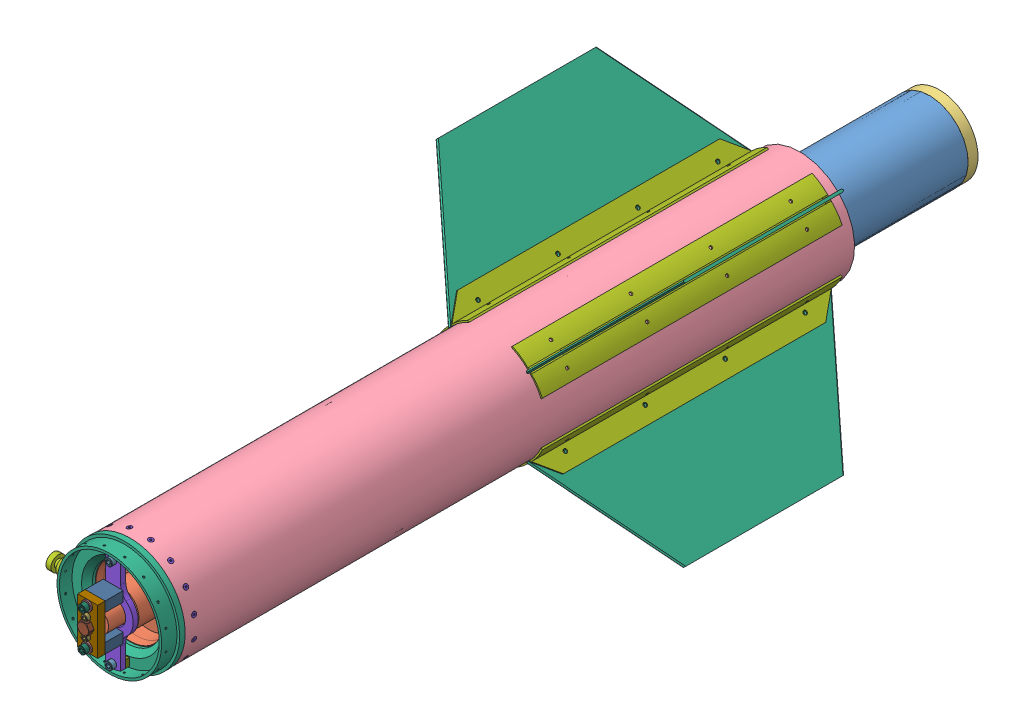
SolidWorks assembly RouseTech_Motor_Retainmenta_Asm, configuration Default. Lengths in mm.
Overall size (316.55 316.55 1102.99).
68 component instances, 28 part files, 35 mates.
Components (placement in the parent):
- RouseTech_15360_Motor_Casing-1: RouseTech_15360_Motor_Casing [Default] at (0 0 12.7) x (0.954187 -0.29921 0) z (0 0 1) size (98.42 98.42 1005.33)
- RouseTech_98mm_Forward_Closure-1: RouseTech_98mm_Forward_Closure [Default] at (0 0 985.1263) x (-1 0.000002 0) z (0 0 1) size (98.27 98.27 85.09)
- RouseTech_98mm_Aft_Closure-1: RouseTech_98mm_Aft_Closure [Default] x (-1 0.000002 0) z (0 0 1) size (98 98 35.31)
- Motor_Fairing-1: Motor_Fairing [Default] at (0 0 1028.4841) x (0.980785 -0.19509 0) z (0 0 -1) size (139.7 139.7 850.9)
- Aft_Motor_Centering_Ring-1: Aft_Motor_Centering_Ring [Default] at (0 0 177.5968) x (0 -1 0) z (0 0 1) size (136.27 136.27 15.88)
- Motor_Bulkhead-1: Motor_Bulkhead [Default] at (0 0 1008.9261) x (-0.19509 -0.980785 0) z (0 0 1) size (139.7 139.7 46.1)
- Rail_Button-1: Rail_Button [Default] at (-69.1975 0 1032.0401) x (0 1 0) z (-1 0 0) size (19.05 19.05 25.33)
- Rail_Button-2: Rail_Button [Default] at (-69.1975 0 188.7093) x (0 1 0) z (-1 0 0) size (19.05 19.05 25.33)
- RouseTech_Retainer_Bracket2-1: RouseTech_Retainer_Bracket2 [Default] at (13.9486 -3.8393 1028.2531) x (0 1 0) z (0 0 1) size (127 50.8 67.37)
  - Retainment_Strap-1: Retainment_Strap [Default] at (-59.6607 23.4736 15.5345) size (127 50.8 6.35)
  - RouseTech_Retaining_CrossBar2-1: RouseTech_Retaining_CrossBar2 [Default] at (33.0493 13.9486 49.507) x (0 -1 0) z (-1 0 0) size (25.4 9.53 58.42)
  - Motor_Retainer_Standoff-1: Motor_Retainer_Standoff [Default] at (-19.0207 13.9486 21.8845) x (0 -1 0) z (0 0 1) size (25.4 12.7 22.86)
  - Motor_Retainer_Standoff-2: Motor_Retainer_Standoff [Default] at (26.6993 13.9486 21.8845) x (0 1 0) z (0 0 1) size (25.4 12.7 22.86)
  - 0.375in-16_1.25in_Bolt_MC-92620A626-1: 0.375in-16_1.25in_Bolt_MC-92620A626 [92620A626] at (3.8393 13.9486 38.3945) size (14.29 16.24 37.79)
  - 10-24_0.375in_Allen_Head_Cap_Screw_MC-91251A240-1: 10-24_0.375in_Allen_Head_Cap_Screw_MC-91251A240 [91251A240] at (-7.2097 13.9486 44.7445) x (-0.923728 -0.383049 0) z (0 0 -1) size (7.92 7.92 15.51)
  - 10-24_0.375in_Allen_Head_Cap_Screw_MC-91251A240-2: 10-24_0.375in_Allen_Head_Cap_Screw_MC-91251A240 [91251A240] at (14.8883 13.9486 44.7445) x (-0.923728 -0.383049 0) z (0 0 -1) size (7.92 7.92 15.51)
  - 0.25in_Lock_Washer-1: 0.25in_Lock_Washer [Default] at (26.6993 13.9486 56.1237) x (-0.923728 -0.383049 0) z (0 0 -1) size (12.32 12.32 1.85)
  - 0.25in_Lock_Washer-2: 0.25in_Lock_Washer [Default] at (-19.0207 13.9486 56.1237) x (-0.923728 -0.383049 0) z (0 0 -1) size (12.32 12.32 1.85)
  - 0.25-20_1.0in_Allen Head_Cap_Screw_MC-91251A542-1: 0.25-20_1.0in_Allen Head_Cap_Screw_MC-91251A542 [91251A542] at (60.9893 13.9486 -3.5155) x (-0.923728 -0.383049 0) z (0 0 -1) size (9.53 9.53 33.14)
  - 0.25-20_1.0in_Allen Head_Cap_Screw_MC-91251A542-2: 0.25-20_1.0in_Allen Head_Cap_Screw_MC-91251A542 [91251A542] at (-53.3107 13.9486 -3.5155) x (-0.923728 -0.383049 0) z (0 0 -1) size (9.53 9.53 33.14)
  - 0.25-20_1.75in_Allen Head_Cap_Screw_MC-91251A548-1: 0.25-20_1.75in_Allen Head_Cap_Screw_MC-91251A548 [91251A548] at (26.6993 13.9486 11.6737) x (-0.923728 -0.383049 0) z (0 0 -1) size (9.53 9.53 52.19)
  - 0.25-20_1.75in_Allen Head_Cap_Screw_MC-91251A548-2: 0.25-20_1.75in_Allen Head_Cap_Screw_MC-91251A548 [91251A548] at (-19.0207 13.9486 11.6737) x (-0.950943 -0.309366 0) z (0 0 -1) size (9.53 9.53 52.19)
  - RouseTech_Retainer_Spacer-1: RouseTech_Retainer_Spacer [Default] at (60.2908 13.9486 10.772) x (0 -1 0) z (0 0 1) size (19.05 9.53 4.76)
  - RouseTech_Retainer_Spacer-2: RouseTech_Retainer_Spacer [Default] at (-52.6122 13.9486 10.772) x (0 1 0) z (0 0 1) size (19.05 9.53 4.76)
- N2000W_Reload_Assembeled-1: N2000W_Reload_Assembeled [Default] at (0 0 56.2356) x (-0.683365 0.730076 0) z (0.730076 0.683365 0) size (129.43 1050.01 129.43)
  - N2000W_Grain-1: N2000W_Grain [Default] at origin size (85.22 152.4 85.22)
  - N2000W_Grain-2: N2000W_Grain [Default] at (0 457.2 0) x (0.999641 0 -0.02679) z (0.02679 0 0.999641) size (85.22 152.4 85.22)
  - N2000W_Grain-3: N2000W_Grain [Default] at (0 152.4 0) size (85.22 152.4 85.22)
  - N2000W_Grain-4: N2000W_Grain [Default] at (0 609.6 0) x (0.569996 0 0.821647) z (-0.821647 0 0.569996) size (85.22 152.4 85.22)
  - N2000W_Grain-6: N2000W_Grain [Default] at (0 304.8 0) size (85.22 152.4 85.22)
  - N2000W_Reload_Liner-1: N2000W_Reload_Liner [Default] at (0 -9.144 0) x (0.685714 0 0.727871) z (-0.727871 0 0.685714) size (91.16 936.62 91.16)
  - N2000W_Grain-7: N2000W_Grain [Default] at (0 762 0) size (85.22 152.4 85.22)
  - N2000W_Nozel-1: N2000W_Nozel [Default] at (0 -42.8244 0) x (-0.670154 0 -0.742222) z (-0.742222 0 0.670154) size (91.64 68.22 91.64)
  - N2000W_O_Ring-1: N2000W_O_Ring [Default] at (0 -18.3388 0) x (-0.992176 0 0.124851) z (0.124851 0 0.992176) size (92.2 5.18 92.2)
  - N2000W_O_Ring-2: N2000W_O_Ring [Default] at (0 933.577 0) x (0.982844 0 -0.18444) z (0.18444 0 0.982844) size (92.2 5.18 92.2)
  - N2000W_Forward_Seal_Disc-1: N2000W_Forward_Seal_Disc [Default] at (0 930.9862 0) size (92.15 7.62 92.15)
  - Part7^N2000W_Reload_Assembeled-1: Part7^N2000W_Reload_Assembeled [Default] at origin (virtual)
  - Part8^N2000W_Reload_Assembeled-1: Part8^N2000W_Reload_Assembeled [Default] at origin (virtual)
  - N2000W_Smoke_Grain-1: N2000W_Smoke_Grain [Default] at (0 930.9862 0) x (1 0 0) z (0 1 0) size (32.89 32.89 50.75)
  - N2000W_Smoke_Grain_Liner-1: N2000W_Smoke_Grain_Liner [Default] at (0 930.9862 0) x (1 0 0) z (0 1 0) size (38.1 38.1 50.8)
- Fin-1: Fin [Default] at (-49.3914 49.3914 380.7841) x (0 0 1) z (-0.707107 -0.707107 0) size (387.35 152.4 3.17)
- Fin-4: Fin [Default] at (49.3914 49.3914 380.7841) x (0 0 1) z (-0.707107 0.707107 0) size (387.35 152.4 3.17)
- Fin-3: Fin [Default] at (49.3914 -49.3914 380.7841) x (0 0 1) z (0.707107 0.707107 0) size (387.35 152.4 3.17)
- Fin-2: Fin [Default] at (-49.3914 -49.3914 380.7841) x (0 0 1) z (0.707107 -0.707107 0) size (387.35 152.4 3.17)
- Fin_Clamp_Half-1: Fin_Clamp_Half [Default] at (-48.2689 50.5139 380.7841) x (0.707107 0.707107 0) z (0 0 1) size (25.4 30.18 381)
- Fin_Clamp_Half-2: Fin_Clamp_Half [Default] at (-50.5139 48.2689 380.7841) x (-0.707107 -0.707107 0) z (0 0 -1) size (25.4 30.18 381)
- Fin_Clamp_Half-3: Fin_Clamp_Half [Default] at (-48.2689 -50.5139 380.7841) x (0.707107 -0.707107 0) z (0 0 -1) size (25.4 30.18 381)
- Fin_Clamp_Half-4: Fin_Clamp_Half [Default] at (50.5139 -48.2689 380.7841) x (0.707107 0.707107 0) z (0 0 -1) size (25.4 30.18 381)
- Fin_Clamp_Half-5: Fin_Clamp_Half [Default] at (48.2689 50.5139 380.7841) x (-0.707107 0.707107 0) z (0 0 -1) size (25.4 30.18 381)
- Fin_Clamp_Half-6: Fin_Clamp_Half [Default] at (-50.5139 -48.2689 380.7841) x (-0.707107 0.707107 0) z (0 0 1) size (25.4 30.18 381)
- Fin_Clamp_Half-7: Fin_Clamp_Half [Default] at (48.2689 -50.5139 380.7841) x (-0.707107 -0.707107 0) z (0 0 1) size (25.4 30.18 381)
- Fin_Clamp_Half-8: Fin_Clamp_Half [Default] at (50.5139 48.2689 380.7841) x (0.707107 -0.707107 0) z (0 0 1) size (25.4 30.18 381)
- 3.0mm_8mm_Counter_Sunk_Hex_Screw-1: 3.0mm_8mm_Counter_Sunk_Hex_Screw [91294A128] at (-34.4176 51.5095 1015.7841) x (0.691343 0.46194 -0.555569) z (0.55557 -0.83147 0) size (6 6 8.16)
- 3.0mm_8mm_Counter_Sunk_Hex_Screw-2: 3.0mm_8mm_Counter_Sunk_Hex_Screw [91294A128] at (-51.5095 34.4176 1015.7841) x (0.46194 0.691343 -0.555569) z (0.83147 -0.55557 0) size (6 6 8.16)
- 3.0mm_8mm_Counter_Sunk_Hex_Screw-3: 3.0mm_8mm_Counter_Sunk_Hex_Screw [91294A128] at (-60.7596 12.0858 1015.7841) x (0.162212 0.815494 -0.555569) z (0.980785 -0.19509 0) size (6 6 8.16)
- 3.0mm_8mm_Counter_Sunk_Hex_Screw-4: 3.0mm_8mm_Counter_Sunk_Hex_Screw [91294A128] at (-60.7596 -12.0858 1015.7841) x (-0.162212 0.815494 -0.555569) z (0.980785 0.19509 0) size (6 6 8.16)
- 3.0mm_8mm_Counter_Sunk_Hex_Screw-5: 3.0mm_8mm_Counter_Sunk_Hex_Screw [91294A128] at (-51.5095 -34.4176 1015.7841) x (-0.46194 0.691343 -0.555569) z (0.83147 0.55557 0) size (6 6 8.16)
- 3.0mm_8mm_Counter_Sunk_Hex_Screw-6: 3.0mm_8mm_Counter_Sunk_Hex_Screw [91294A128] at (-34.4176 -51.5095 1015.7841) x (-0.691343 0.46194 -0.555569) z (0.55557 0.83147 0) size (6 6 8.16)
- 3.0mm_8mm_Counter_Sunk_Hex_Screw-7: 3.0mm_8mm_Counter_Sunk_Hex_Screw [91294A128] at (-12.0858 -60.7596 1015.7841) x (-0.815494 0.162212 -0.555569) z (0.19509 0.980785 0) size (6 6 8.16)
- 3.0mm_8mm_Counter_Sunk_Hex_Screw-8: 3.0mm_8mm_Counter_Sunk_Hex_Screw [91294A128] at (12.0858 -60.7596 1015.7841) x (-0.815494 -0.162212 -0.555569) z (-0.19509 0.980785 0) size (6 6 8.16)
- 3.0mm_8mm_Counter_Sunk_Hex_Screw-9: 3.0mm_8mm_Counter_Sunk_Hex_Screw [91294A128] at (34.4176 -51.5095 1015.7841) x (-0.691343 -0.46194 -0.555569) z (-0.55557 0.83147 0) size (6 6 8.16)
- 3.0mm_8mm_Counter_Sunk_Hex_Screw-10: 3.0mm_8mm_Counter_Sunk_Hex_Screw [91294A128] at (51.5095 -34.4176 1015.7841) x (-0.46194 -0.691343 -0.555569) z (-0.83147 0.55557 0) size (6 6 8.16)
- 3.0mm_8mm_Counter_Sunk_Hex_Screw-11: 3.0mm_8mm_Counter_Sunk_Hex_Screw [91294A128] at (60.7596 -12.0858 1015.7841) x (-0.162212 -0.815494 -0.555569) z (-0.980785 0.19509 0) size (6 6 8.16)
- 3.0mm_8mm_Counter_Sunk_Hex_Screw-12: 3.0mm_8mm_Counter_Sunk_Hex_Screw [91294A128] at (60.7596 12.0858 1015.7841) x (0.162212 -0.815494 -0.555569) z (-0.980785 -0.19509 0) size (6 6 8.16)
- 3.0mm_8mm_Counter_Sunk_Hex_Screw-13: 3.0mm_8mm_Counter_Sunk_Hex_Screw [91294A128] at (51.5095 34.4176 1015.7841) x (0.46194 -0.691343 -0.555569) z (-0.83147 -0.55557 0) size (6 6 8.16)
- 3.0mm_8mm_Counter_Sunk_Hex_Screw-14: 3.0mm_8mm_Counter_Sunk_Hex_Screw [91294A128] at (34.4176 51.5095 1015.7841) x (0.691343 -0.46194 -0.555569) z (-0.55557 -0.83147 0) size (6 6 8.16)
- 3.0mm_8mm_Counter_Sunk_Hex_Screw-15: 3.0mm_8mm_Counter_Sunk_Hex_Screw [91294A128] at (12.0858 60.7596 1015.7841) x (0.815494 -0.162212 -0.555569) z (-0.19509 -0.980785 0) size (6 6 8.16)
- 3.0mm_8mm_Counter_Sunk_Hex_Screw-16: 3.0mm_8mm_Counter_Sunk_Hex_Screw [91294A128] at (-12.0858 60.7596 1015.7841) x (0.815494 0.162212 -0.555569) z (0.19509 -0.980785 0) size (6 6 8.16)
Mates (geometry in assembly coordinates):
- Coincident1: coincident aligned: axis of RouseTech_98mm_Aft_Closure-1 through (0 0 35.306) axis (0 0 -1); axis of RouseTech_15360_Motor_Casing-1 through (0 0 1018.032) axis (0 0 -1)
- Coincident2: coincident anti-aligned: plane of RouseTech_98mm_Aft_Closure-1 through (0 0 12.7) normal (0 0 1); plane of RouseTech_15360_Motor_Casing-1 through (0 0 12.7) normal (0 0 -1)
- Coincident3: coincident aligned: axis of RouseTech_98mm_Forward_Closure-1 through (0 0 1018.032) axis (0 0 -1); axis of RouseTech_15360_Motor_Casing-1 through (0 0 1018.032) axis (0 0 -1)
- Coincident4: coincident anti-aligned: plane of RouseTech_98mm_Forward_Closure-1 through (0 0 1018.032) normal (0 0 -1); plane of RouseTech_15360_Motor_Casing-1 through (0 0 1018.032) normal (0 0 1)
- Coincident7: coincident anti-aligned: axis of RouseTech_15360_Motor_Casing-1 through (0 0 1018.032) axis (0 0 -1); axis of Motor_Fairing-1 through (0 0 177.5841) axis (0 0 1)
- Parallel3: parallel: axis of RouseTech_15360_Motor_Casing-1 through (0 0 1018.032) axis (0 0 -1); plane of assembly
- Coincident54: coincident aligned: axis of RouseTech_98mm_Forward_Closure-1 through (0 0 1041.2603) axis (0 0 1); axis of Motor_Bulkhead-1 through (0 0 1028.4841) axis (0 0 1)
- Coincident56: coincident anti-aligned: plane of RouseTech_98mm_Forward_Closure-1 through (0 0 1028.4841) normal (0 0 1); plane of Motor_Bulkhead-1 through (0 0 1028.4841) normal (0 0 -1)
- Parallel4: parallel: plane of assembly through (0 0 0) normal (0 1 0); axis of Motor_Bulkhead-1 through (-57.15 0 1032.0401) axis (-1 0 0)
- Coincident88: coincident anti-aligned: axis of Motor_Bulkhead-1 through (-57.15 0 1032.0401) axis (-1 0 0); axis of Rail_Button-1 through (-81.5851 0 1032.0401) axis (1 0 0)
- Concentric1: concentric anti-aligned: cylinder of Motor_Bulkhead-1 through (0 0 1055.0271) axis (0 0 -1) radius 69.85; cylinder of Rail_Button-1 through (0 0 986.2827) axis (0 0 1) radius 69.85
- Coincident89: coincident anti-aligned: plane of Motor_Fairing-1; plane of Fin-1 through (-49.3914 49.3914 380.7841) normal (-0.707107 -0.707107 0)
- Parallel8: parallel aligned: axis of Motor_Fairing-1 through (0 0 177.5841) axis (0 0 1); line of Fin-1 through (-48.2689 50.5139 188.7413) axis (0 0 1)
- Tangent1: tangent anti-aligned: cylinder of Motor_Fairing-1 through (0 0 177.5841) axis (0 0 1) radius 69.85; plane of Fin-1 through (-50.5139 48.2689 380.7841) normal (0.707107 -0.707107 0)
- Coincident92: coincident anti-aligned: axis of Motor_Fairing-1 through (-68.198 0 188.7093) axis (-1 0 0); axis of Aft_Motor_Centering_Ring-1 through (66.6674 0 188.7093) axis (1 0 0)
- Coincident93: coincident aligned: axis of RouseTech_15360_Motor_Casing-1 through (0 0 1018.032) axis (0 0 -1); axis of Aft_Motor_Centering_Ring-1 through (0 0 183.9468) axis (0 0 -1)
- Coincident99: coincident anti-aligned: axis of Motor_Fairing-1 through (-68.198 0 188.7093) axis (-1 0 0); axis of Rail_Button-2 through (-81.5851 0 188.7093) axis (1 0 0)
- Concentric2: concentric aligned: cylinder of Motor_Fairing-1 through (0 0 177.5841) axis (0 0 1) radius 69.85; cylinder of Rail_Button-2 through (0 0 142.9519) axis (0 0 1) radius 69.85
- Coincident102: coincident anti-aligned: axis of Motor_Fairing-1 through (-68.4738 13.6203 1015.7841) axis (0.980785 -0.19509 0); axis of Motor_Bulkhead-1 through (-65.8502 13.0984 1015.7841) axis (-0.980785 0.19509 0)
- Coincident106: coincident anti-aligned: axis of RouseTech_98mm_Forward_Closure-1 through (0 0 1043.5463) axis (0 0 1); axis of RouseTech_Retainer_Bracket2-1/Retainment_Strap-1 through (0 0 1050.1376) axis (0 0 -1)
- Coincident107: coincident aligned: axis of Motor_Bulkhead-1 through (0 -57.15 1018.4511) axis (0 0 1); axis of RouseTech_Retainer_Bracket2-1/Retainment_Strap-1 through (0 -57.15 1043.7876) axis (0 0 1)
- Coincident108: coincident anti-aligned: plane of Motor_Bulkhead-1 through (0 0 1039.0251) normal (0 0 1); plane of RouseTech_Retainer_Bracket2-1/RouseTech_Retainer_Spacer-2 through (-9.525 -61.214 1039.0251) normal (0 0 -1)
- Coincident109: coincident aligned: axis of RouseTech_15360_Motor_Casing-1 through (0 0 1018.032) axis (0 0 -1); axis of N2000W_Reload_Assembeled-1/N2000W_Reload_Liner-1 through (0 0 983.7166) axis (0 0 -1)
- Coincident112: coincident anti-aligned: line of Fin-1 through (-48.2689 50.5139 188.7413) axis (0 0 1); line of Fin_Clamp_Half-1 through (-48.2689 50.5139 571.2841) axis (0 0 -1)
- Coincident113: coincident anti-aligned: plane of Fin-1 through (-48.2689 50.5139 574.4591) normal (0.707107 0.707107 0); plane of Fin_Clamp_Half-1 through (-48.2689 50.5139 571.2841) normal (-0.707107 -0.707107 0)
- Coincident114: coincident anti-aligned: plane of Fin-1 through (-50.5139 48.2689 574.4591) normal (-0.707107 -0.707107 0); plane of Fin_Clamp_Half-2 through (-50.5139 48.2689 190.2841) normal (0.707107 0.707107 0)
- Coincident115: coincident aligned: line of Fin-1 through (-50.5139 48.2689 188.7413) axis (0 0 1); line of Fin_Clamp_Half-2 through (-50.5139 48.2689 190.2841) axis (0 0 1)
- Coincident116: coincident aligned: plane of Fin_Clamp_Half-1 through (1.1225 1.1225 190.2841) normal (0 0 -1); plane of Fin_Clamp_Half-2 through (-1.1225 -1.1225 190.2841) normal (0 0 -1)
- Coincident118: coincident anti-aligned: plane of Fin-1; plane of Fin_Clamp_Half-2 through (-50.5139 48.2689 380.7841) normal (0 0 1)
- Coincident119: coincident aligned: axis of Motor_Fairing-1 through (-38.8066 58.0782 1015.7841) axis (0.55557 -0.83147 0); axis of 3.0mm_8mm_Counter_Sunk_Hex_Screw-1 through (-38.7232 57.9534 1015.7841) axis (0.55557 -0.83147 0)
- Coincident120: coincident: cone of Motor_Fairing-1 through (-38.8066 58.0782 1015.7841) axis (0.55557 -0.83147 0); circle of 3.0mm_8mm_Counter_Sunk_Hex_Screw-1
- Coincident122: coincident anti-aligned: plane of RouseTech_98mm_Aft_Closure-1 through (0 0 0) normal (0 0 -1); plane of assembly through (0 0 0) normal (0 0 1)
- Coincident123: coincident: axis of Motor_Fairing-1 through (0 0 177.5841) axis (0 0 1); point of assembly
- Tangent2: tangent: plane of RouseTech_98mm_Aft_Closure-1 through (0 0 35.306) normal (0 0 1); face of N2000W_Reload_Assembeled-1/N2000W_O_Ring-1
- Distance1: distance = 50.8 mm: axis of Fin_Clamp_Half-2 through (-56.5756 54.3305 228.3841) axis (-0.707107 -0.707107 0); plane of Motor_Fairing-1 through (0 0 177.5841) normal (0 0 -1)
